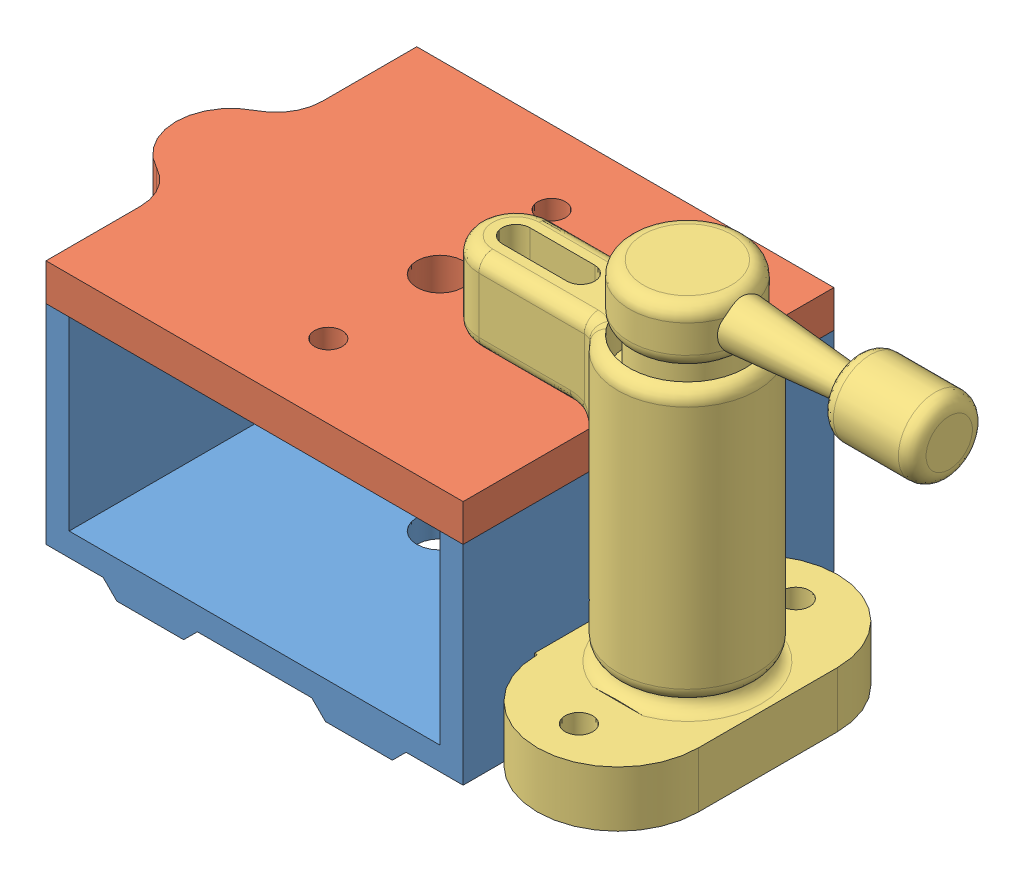
SolidWorks assembly Assem3, configuration Default. Lengths in mm.
Overall size (176.5 97 82.01).
3 component instances, 3 part files, 4 mates.
Components (placement in the parent):
- jig body-1: jig body [Default] at (-55.8731 -26.7025 -21.2003) size (102 47.96 80)
- latch plate-2: latch plate [Default] at (29.1269 13.2975 -21.2003) x (-1 0 0) z (0 1 0) size (102 80 8)
- base_plate-1: base_plate [Default] at (64.6261 -26.7025 28.4157) x (-1 0 0) z (0 1 0) size (101.5 64.78 89.04)
Mates (geometry in assembly coordinates):
- Coincident4: coincident anti-aligned: plane of jig body-1 through (-55.8731 13.2975 58.7997) normal (0 1 0); plane of latch plate-2 through (-70.8731 13.2975 38.3956) normal (0 -1 0)
- Concentric2: concentric anti-aligned: cylinder of jig body-1 through (-60.8731 -58.5353 18.7997) axis (0 1 0) radius 12; cylinder of latch plate-2 through (-60.8731 21.2975 18.7997) axis (0 -1 0) radius 12
- Coincident6: coincident anti-aligned: plane of jig body-1 through (-55.8731 -26.7025 58.7997) normal (0 1 0); plane of base_plate-1 through (64.6261 -26.7025 28.4157) normal (0 -1 0)
- Coincident7: coincident anti-aligned: plane of jig body-1 through (29.1269 -26.7025 58.7997) normal (1 0 0); plane of base_plate-1 through (29.1269 89.1377 -6.1216) normal (-1 0 0)
